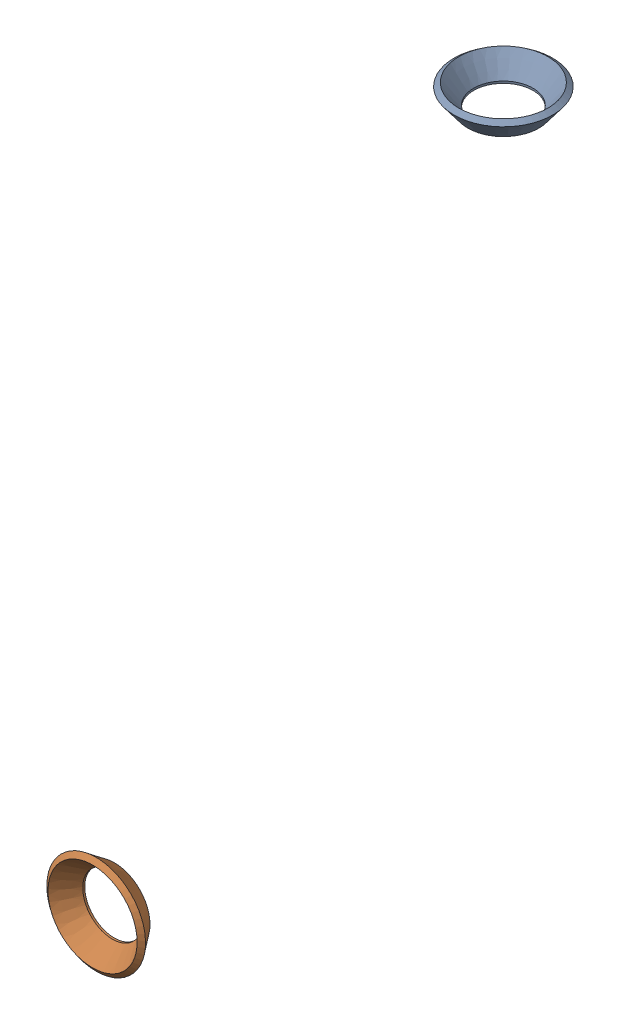
SolidWorks assembly Pipe 3, configuration Default. Lengths in mm.
Overall size (17.59 100.93 82.02).
2 component instances, 1 part files, 4 mates.
Components (placement in the parent):
- Flared pipe end - .5 inch-1: Flared pipe end - .5 inch [Default<As Machined>] at (0 -188.1312 291.3922) x (1 0 0.00017) z (0 1 0) size (17.59 17.59 3.89)
- Flared pipe end - .5 inch-2: Flared pipe end - .5 inch [Default<As Machined>] at (0 -276.3764 360.7276) x (1 -0.00017 0) z (0 0 1) size (17.59 17.59 3.89)
Mates (geometry in assembly coordinates):
- Coincident1032: coincident: plane of ? through (0 -188.1312 291.3922) normal (0 1 0); plane of Flared pipe end - .5 inch-1 through (0.0009 -188.1312 286.109) normal (0 -1 0)
- Concentric658: concentric: circle of ?; circle of Flared pipe end - .5 inch-1
- Coincident1033: coincident: plane of ? through (0 -276.3764 360.7276) normal (0 0 1); plane of Flared pipe end - .5 inch-2 through (0.0009 -271.0932 360.7276) normal (0 0 -1)
- Concentric659: concentric: circle of ?; circle of Flared pipe end - .5 inch-2
